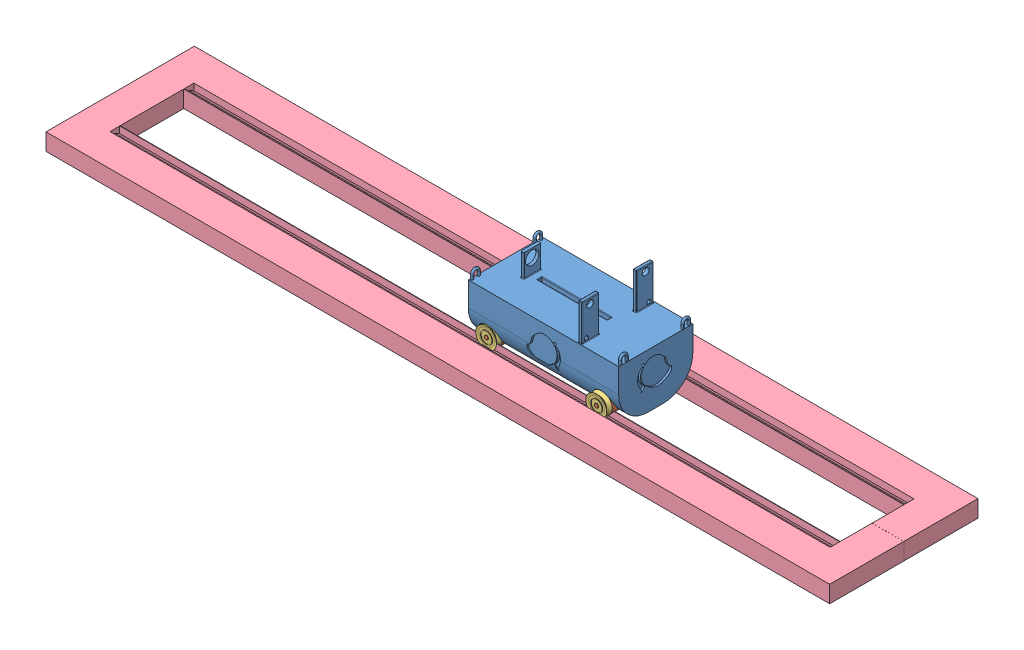
SolidWorks assembly Assem2, configuration Default. Lengths in mm.
Overall size (530.39 284.2 88.95).
8 component instances, 4 part files, 12 mates.
Components (placement in the parent):
- Kart-1: Kart [Default] at (-2.562 58.68 49.9027) size (90.17 54.03 44.45)
- Axel-1: Axel [Default] at (-23.879 42.3815 91.1788) x (0.812512 -0.582945 0) z (0.582945 0.812512 0) size (12.19 47.52 12.19)
- wheel-1: wheel [Default] at (-10.3554 43.4115 67.611) x (0 0 -1) z (0.997112 0.075941 0) size (3.41 12.39 12.39)
- wheel-2: wheel [Default] at (58.1386 42.3815 69.9848) x (0 0 -1) z (1 0 0) size (3.41 12.39 12.39)
- wheel-3: wheel [Default] at (-37.438 42.6991 73.9796) x (0 0 1) z (-0.999726 0.023417 0) size (3.41 12.39 12.39)
- wheel-4: wheel [Default] at (31.013 42.3815 76.3534) x (0 0 1) z (-1 0 0) size (3.41 12.39 12.39)
- Axel-2: Axel [Default] at (44.5758 42.3815 93.5526) x (0.880462 0.474118 0) z (-0.474118 0.880462 0) size (12.19 47.52 12.19)
- Part2-1: Part2 [Default] at (170.0125 30.1152 86.0435) size (530.39 284.2 88.95)
Mates (geometry in assembly coordinates):
- Concentric1: concentric anti-aligned: cylinder of Kart-1 through (-23.879 42.3815 94.3527) axis (0 0 -1) radius 6.35; cylinder of Axel-1 through (-23.879 42.3815 50.4118) axis (0 0 1) radius 6.096
- Concentric2: concentric anti-aligned: cylinder of Kart-1 through (44.5758 42.3815 94.3527) axis (0 0 -1) radius 6.35; cylinder of Axel-2 through (44.5758 42.3815 52.7856) axis (0 0 1) radius 6.096
- Concentric3: concentric anti-aligned: cylinder of Axel-1 through (-23.879 42.3815 94.557) axis (0 0 -1) radius 1.143; cylinder of wheel-1 through (-23.879 42.3815 86.6756) axis (0 0 1) radius 1.1608
- Coincident1: coincident aligned: plane of Axel-1 through (-23.879 42.3815 91.1788) normal (0 0 1); circle of wheel-1
- Concentric4: concentric anti-aligned: cylinder of Axel-1 through (-23.879 42.3815 47.0336) axis (0 0 1) radius 1.143; cylinder of wheel-3 through (-23.879 42.3815 54.915) axis (0 0 -1) radius 1.1608
- Concentric5: concentric anti-aligned: cylinder of Axel-1 through (-23.879 42.3815 47.0336) axis (0 0 1) radius 1.143; cylinder of wheel-3 through (-23.879 42.3815 54.915) axis (0 0 -1) radius 1.1608
- Coincident2: coincident aligned: plane of Axel-1 through (-23.879 42.3815 50.4118) normal (0 0 -1); circle of wheel-3
- Concentric6: concentric anti-aligned: cylinder of wheel-4 through (44.5758 42.3815 57.2888) axis (0 0 -1) radius 1.1608; cylinder of Axel-2 through (44.5758 42.3815 49.4074) axis (0 0 1) radius 1.143
- Coincident3: coincident aligned: circle of wheel-4; plane of Axel-2 through (44.5758 42.3815 52.7856) normal (0 0 -1)
- Concentric7: concentric anti-aligned: cylinder of wheel-2 through (44.5758 42.3815 89.0494) axis (0 0 1) radius 1.1608; cylinder of Axel-2 through (44.5758 42.3815 96.9308) axis (0 0 -1) radius 1.143
- Coincident4: coincident aligned: circle of wheel-2; plane of Axel-2 through (44.5758 42.3815 93.5526) normal (0 0 1)
- Parallel1: parallel anti-aligned: plane of Kart-1 through (-34.7366 34.4139 94.3527) normal (0 -1 0); plane of Part2-1 through (170.0125 40.2752 86.0435) normal (0 1 0)
